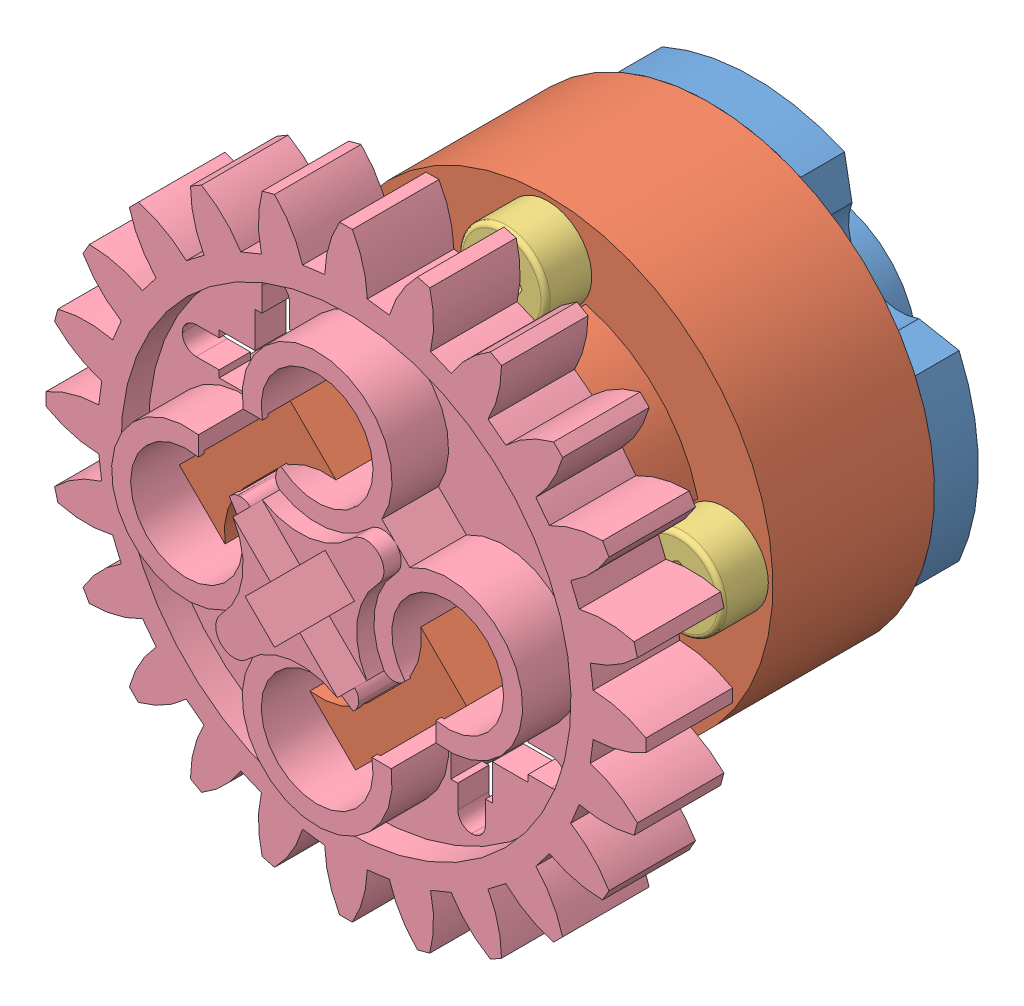
SolidWorks assembly Adapter-Servo-Zahnrad-24Z, configuration Standard. Lengths in mm.
Overall size (36.77 36.77 22.65).
7 component instances, 4 part files, 12 mates.
Components (placement in the parent):
- Servo-Horn-4er-modifiziert-1: Servo-Horn-4er-modifiziert [Standard] at origin size (19.5 19.5 5.7)
- Adapter-Servo-Zahnrad-24Z-1: Adapter-Servo-Zahnrad-24Z [Standard] at (0 0 8.8) x (-0.707107 0.707107 0) z (0 0 1) size (19.5 19.5 16.75)
- DIN 912 M2 x 10 --- 10N-5: DIN 912 M2 x 10 --- 10N [DIN 912 M2 x 10 --- 10N] at (0 7.65 10.8) x (0 0 -1) z (0 1 0) size (12 3.8 3.8)
- DIN 912 M2 x 10 --- 10N-6: DIN 912 M2 x 10 --- 10N [DIN 912 M2 x 10 --- 10N] at (7.65 0 10.8) x (0 0 -1) z (1 0 0) size (12 3.8 3.8)
- DIN 912 M2 x 10 --- 10N-7: DIN 912 M2 x 10 --- 10N [DIN 912 M2 x 10 --- 10N] at (0 -7.65 10.8) x (0 0 -1) z (0 -1 0) size (12 3.8 3.8)
- DIN 912 M2 x 10 --- 10N-8: DIN 912 M2 x 10 --- 10N [DIN 912 M2 x 10 --- 10N] at (-7.65 0 10.8) x (0 0 -1) z (-1 0 0) size (12 3.8 3.8)
- Lego Zahnrad 24Z-1: Lego Zahnrad 24Z [Standard] at (0 0 15.675) x (0.707107 -0.707107 0) z (0 0 1) size (26 26 7.75)
Mates (geometry in assembly coordinates):
- Deckungsgleich9: coincident aligned: plane of Servo-Horn-4er-modifiziert-1 through (0 0 0) normal (1 0 0); plane of assembly through (0 0 0) normal (1 0 0)
- Deckungsgleich10: coincident aligned: plane of Servo-Horn-4er-modifiziert-1 through (0 0 0) normal (0 0 1); plane of assembly through (0 0 0) normal (0 0 1)
- Deckungsgleich11: coincident aligned: plane of Servo-Horn-4er-modifiziert-1 through (0 0 0) normal (0 1 0); plane of assembly through (0 0 0) normal (0 1 0)
- Deckungsgleich12: coincident anti-aligned: plane of Servo-Horn-4er-modifiziert-1 through (0 4.5 1.8) normal (0 0 1); plane of Adapter-Servo-Zahnrad-24Z-1 through (0 0 1.8) normal (0 0 -1)
- Konzentrisch3: concentric aligned: cylinder of Servo-Horn-4er-modifiziert-1 through (0 0 0) axis (0 0 1) radius 4.1; cylinder of Adapter-Servo-Zahnrad-24Z-1 through (0 0 1.8) axis (0 0 1) radius 9.75
- Konzentrisch4: concentric aligned: cylinder of Servo-Horn-4er-modifiziert-1 through (0 7.65 -3.1) axis (0 0 1) radius 0.9; cylinder of Adapter-Servo-Zahnrad-24Z-1 through (0 7.65 1.8) axis (0 0 1) radius 1.05
- Konzentrisch5: concentric aligned: cylinder of Adapter-Servo-Zahnrad-24Z-1 through (0 7.65 1.8) axis (0 0 1) radius 1.05; cylinder of DIN 912 M2 x 10 --- 10N-5 through (0 7.65 42.55) axis (0 0 1) radius 1
- Deckungsgleich13: coincident anti-aligned: plane of Adapter-Servo-Zahnrad-24Z-1 through (0 0 8.8) normal (0 0 1); plane of DIN 912 M2 x 10 --- 10N-5 through (-1.9 7.65 8.8) normal (0 0 -1)
- Deckungsgleich14: coincident anti-aligned: plane of DIN 912 M2 x 10 --- 10N-5; plane of assembly through (0 0 0) normal (1 0 0)
- Konzentrisch6: concentric anti-aligned: cylinder of Servo-Horn-4er-modifiziert-1 through (0 0 0) axis (0 0 1) radius 2.95; line of Lego Zahnrad 24Z-1 through (0 0 19.9375) axis (0 0 -1)
- Parallel1: parallel aligned: plane of Adapter-Servo-Zahnrad-24Z-1 through (-2.687 2.687 18.55) normal (0.707107 -0.707107 0); plane of Lego Zahnrad 24Z-1
- Deckungsgleich17: coincident anti-aligned: plane of Adapter-Servo-Zahnrad-24Z-1 through (0 0 12.55) normal (0 0 1); plane of Lego Zahnrad 24Z-1 through (0 0 12.55) normal (0 0 -1)
